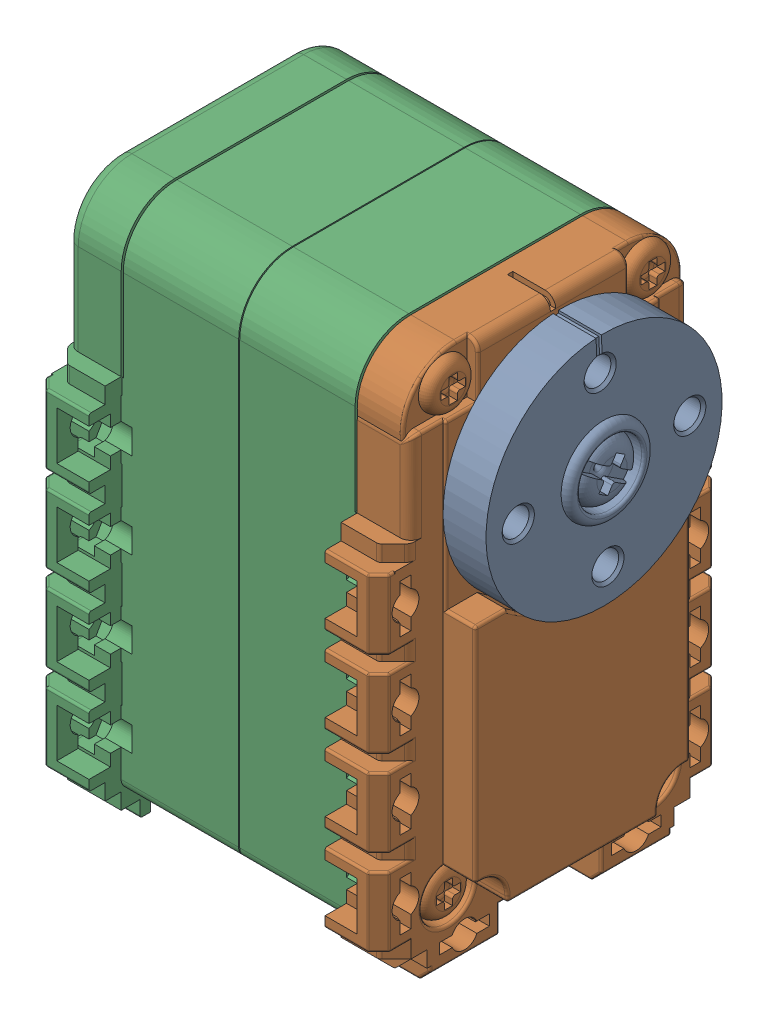
SolidWorks assembly A-Act-001, configuration Default. Lengths in mm.
Overall size (40.85 50 32).
2 component instances, 2 part files, 2 mates.
Components (placement in the parent):
- P-Act-002-1: P-Act-002 [Default] at (15.66 50.1246 5.628) x (0 0.99898 0.045152) z (0 0.045152 -0.99898) size (22 14.85 22)
- P-Act-003-1: P-Act-003 [Default] at (-3.34 38.1246 5.628) x (0 -1 0) z (0 0 -1) size (50 38.01 32)
Mates (geometry in assembly coordinates):
- Concentric1: concentric aligned: cylinder of ax12_wheel-1 through (3.66 50.1246 5.628) axis (1 0 0) radius 3; cylinder of ax12_box-1 through (3.66 50.1246 5.628) axis (1 0 0) radius 3
- Coincident1: coincident anti-aligned: plane of ax12_wheel-1 through (3.66 50.1246 5.628) normal (-1 0 0); plane of ax12_box-1 through (3.66 50.1246 5.628) normal (1 0 0)
